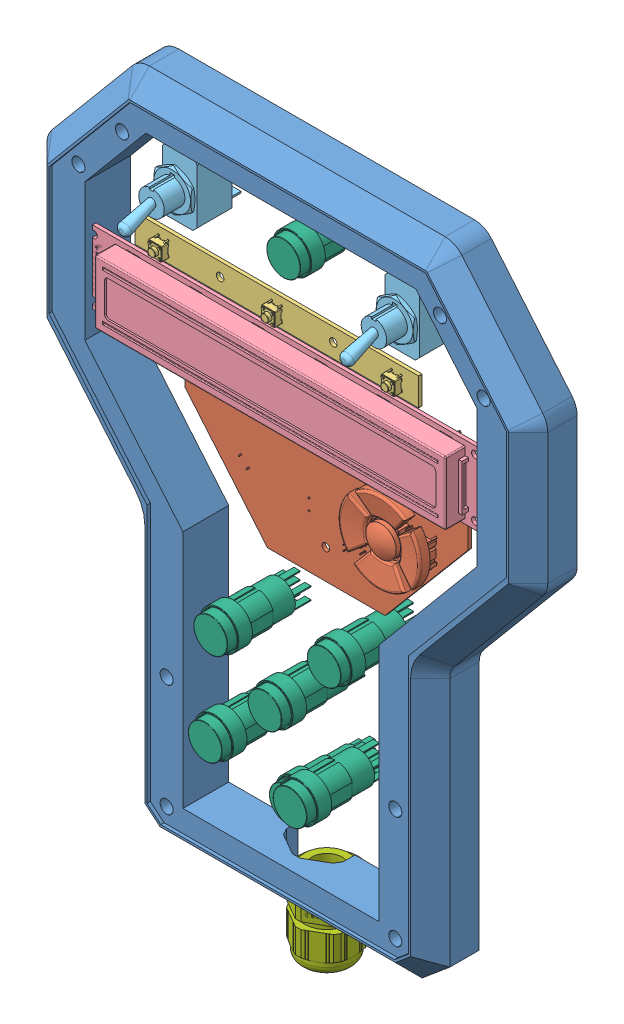
SolidWorks assembly Montagem004, configuration Valor predeterminado. Lengths in mm.
Overall size (230 327 64.69).
15 component instances, 8 part files, 7 mates.
Components (placement in the parent):
- 4 - TEC02 - Moldura-1: 4 - TEC02 - Moldura [Valor predeterminado] at (-13.0658 -145.3846 -11.25) size (230 300 22.5)
- PCB_IHM_Reduzida-1: PCB_IHM_Reduzida [Valor predeterminado] at (39.1853 41.8659 -11.4844) size (130 70 21.73)
- Teclado_Superior_Reduzido-1: Teclado_Superior_Reduzido [Valor predeterminado] at (36.4296 81.2047 8.492) size (130.25 12.75 8.5)
- LCD Display 4002-1: LCD Display 4002 [Valor predeterminado] at (-14.9844 57.5604 1.6961) size (182 33.5 13.65)
- BCV3 112 103 - Controle chave geral-1: BCV3 112 103 - Controle chave geral [Default] at (-63.5121 109.0739 -2.2468) size (17 29 51.5)
- BCV3 112 103 - Controle chave geral-2: BCV3 112 103 - Controle chave geral [Default] at (39.4542 109.4415 -1.4089) size (17 29 51.5)
- BCV3 112 102 - Controle botão-1: BCV3 112 102 - Controle botão [Valor predeterminado] at (6.6492 -44.8276 -0.65) x (1 0 0) z (0 -1 0) size (17.7 39.7 17.7)
- BCV3 112 102 - Controle botão-2: BCV3 112 102 - Controle botão [Valor predeterminado] at (-34.0744 -46.9182 10.7) x (1 0 0) z (0 -1 0) size (17.7 39.7 17.7)
- BCV3 112 102 - Controle botão-3: BCV3 112 102 - Controle botão [Valor predeterminado] at (-36.5597 -90.5451 10.7) x (1 0 0) z (0 -1 0) size (17.7 39.7 17.7)
- BCV3 112 102 - Controle botão-4: BCV3 112 102 - Controle botão [Valor predeterminado] at (11.8079 -87.6667 20.15) x (1 0 0) z (0 -1 0) size (17.7 39.7 17.7)
- BCV3 112 102 - Controle botão-5: BCV3 112 102 - Controle botão [Valor predeterminado] at (-11.8595 -109.1762 -1.8) x (1 0 0) z (0 -1 0) size (17.7 39.7 17.7)
- BCV3 112 102 - Controle botão-6: BCV3 112 102 - Controle botão [Valor predeterminado] at (-12.2464 -67.4435 7.65) x (1 0 0) z (0 -1 0) size (17.7 39.7 17.7)
- BCV3 112 102 - Controle botão-7: BCV3 112 102 - Controle botão [Valor predeterminado] at (-12.6762 107.5509 -1.3734) x (1 0 0) z (0 -1 0) size (17.7 39.7 17.7)
- PRENSA CABO STECK PG 13,5 S802 LI-1: PRENSA CABO STECK PG 13,5 S802 LI [Valor predeterminado] at (-13.2037 -162.4668 -11.4731) x (0 -1 0) z (-0.5 0 0.866025) size (36 28.2 26.2)
- hex nut style 1 gradeab_din-1: hex nut style 1 gradeab_din [Hexagon Nut ISO 4032 - M4 - W - N] at (79.9342 98.6154 -1.25) x (0.5 0.866025 0) z (0 0 1) size (7 8.08 3.2)
Mates (geometry in assembly coordinates):
- Coincidente1: coincident aligned: plane of 4 - TEC02 - Moldura-1 through (-13.0658 -145.3846 9.75) normal (0 0 1); plane of BCV3 112 102 - Controle botão-1 through (6.6492 -44.8276 9.75) normal (0 0 1)
- Coincidente4: coincident anti-aligned: plane of 4 - TEC02 - Moldura-1 through (-13.0658 -153.4668 11.25) normal (0 -1 0); plane of PRENSA CABO STECK PG 13,5 S802 LI-1 through (-1.1037 -153.4668 -4.4872) normal (0 1 0)
- Coincidente7: coincident anti-aligned: plane of 4 - TEC02 - Moldura-1 through (-14.9817 -148.4668 2.6269) normal (0 0 -1); plane of PRENSA CABO STECK PG 13,5 S802 LI-1 through (-14.9817 -146.2668 2.6269) normal (0 0 1)
- Coincidente8: coincident anti-aligned: plane of 4 - TEC02 - Moldura-1 through (-26.3037 -148.4668 -16.993) normal (1 0 0); plane of PRENSA CABO STECK PG 13,5 S802 LI-1 through (-26.3037 -146.2668 -16.9832) normal (-1 0 0)
- Concêntrico2: concentric aligned: cylinder of 4 - TEC02 - Moldura-1 through (79.9342 98.6154 -11.25) axis (0 0 1) radius 3; cylinder of hex nut style 1 gradeab_din-1 through (79.9342 98.6154 -4.45) axis (0 0 1) radius 1.65
- Coincidente9: coincident anti-aligned: plane of 4 - TEC02 - Moldura-1 through (83.4342 100.6362 -1.25) normal (-1 0 0); plane of hex nut style 1 gradeab_din-1 through (83.4342 96.5947 -4.45) normal (1 0 0)
- Coincidente10: coincident anti-aligned: plane of 4 - TEC02 - Moldura-1 through (-13.0658 -145.3846 -1.25) normal (0 0 -1); plane of hex nut style 1 gradeab_din-1 through (76.4342 92.5533 -1.25) normal (0 0 1)
